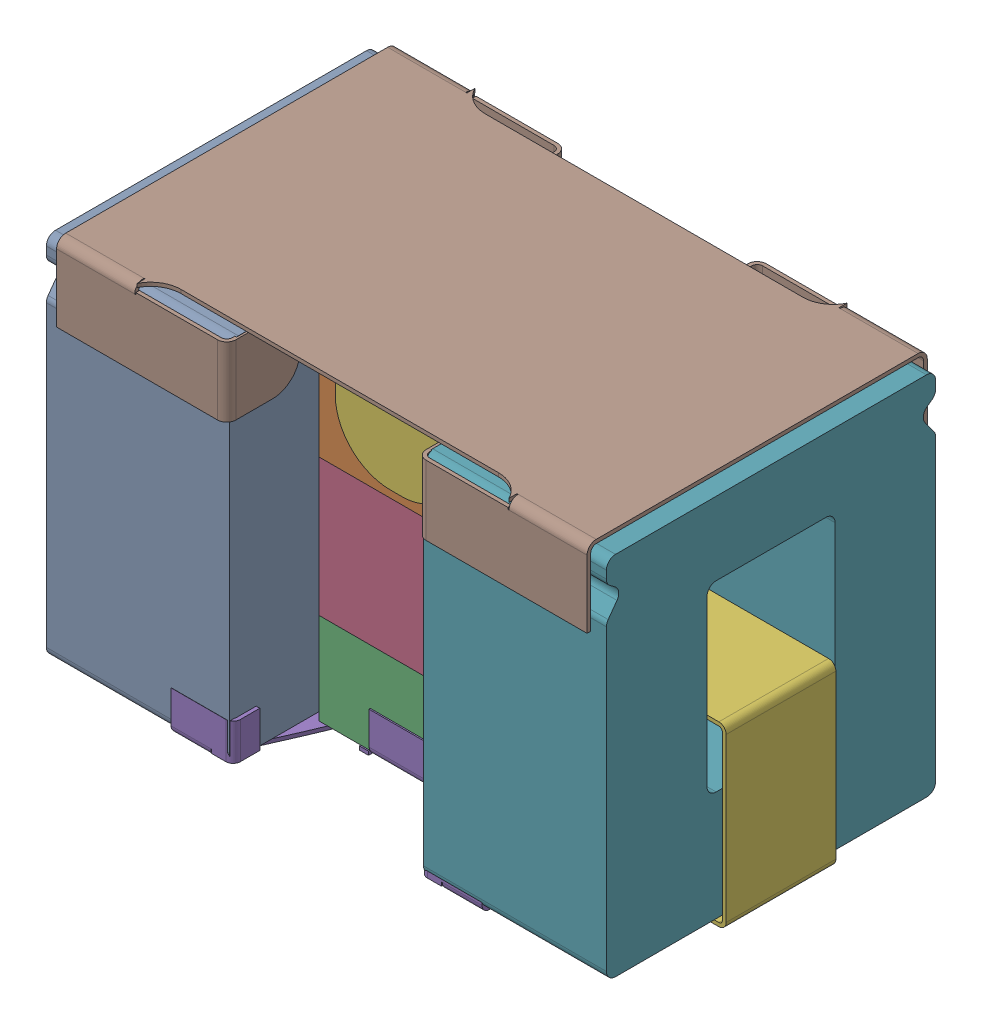
SolidWorks assembly User_Library-filterassy-1, configuration Default. Lengths in mm.
Overall size (3.21 2.06 1.86).
6 component instances, 5 part files, 0 mates.
Components (placement in the parent):
- User_Library-filterassy-1_ferrite001_1-1: User_Library-filterassy-1_ferrite001_1 [Default] at (-1.7182 1.0098 -0.0449) x (0 0 -1) z (1 0 0) size (1.8 2 1)
- User_Library-filterassy-1_0603cap_1-1: User_Library-filterassy-1_0603cap_1 [Default] at (-0.2006 0.895 0.4524) x (0 -1 0) z (1 0 0) size (1.75 0.9 0.95)
- User_Library-filterassy-1_bottom_bracketSLDPRT_1-1: User_Library-filterassy-1_bottom_bracketSLDPRT_1 [Default] at origin size (1.7 0.22 1.8)
- User_Library-filterassy-1_cap_top_hat_1-1: User_Library-filterassy-1_cap_top_hat_1 [Default] at (-0.1923 1.79 0.0135) x (-1 0 0) z (0 0 1) size (3.21 1.79 1)
- User_Library-filterassy-1_ferrite001_1-2: User_Library-filterassy-1_ferrite001_1 [Default] at (0.3475 1.0098 -0.0411) x (0 0 -1) z (1 0 0) size (1.8 2 1)
- User_Library-filterassy-1_top_1-1: User_Library-filterassy-1_top_1 [Default] at (-0.1875 2.0589 -0.0063) x (-1 0 0) z (0 0 1) size (2.9 0.42 1.86)
